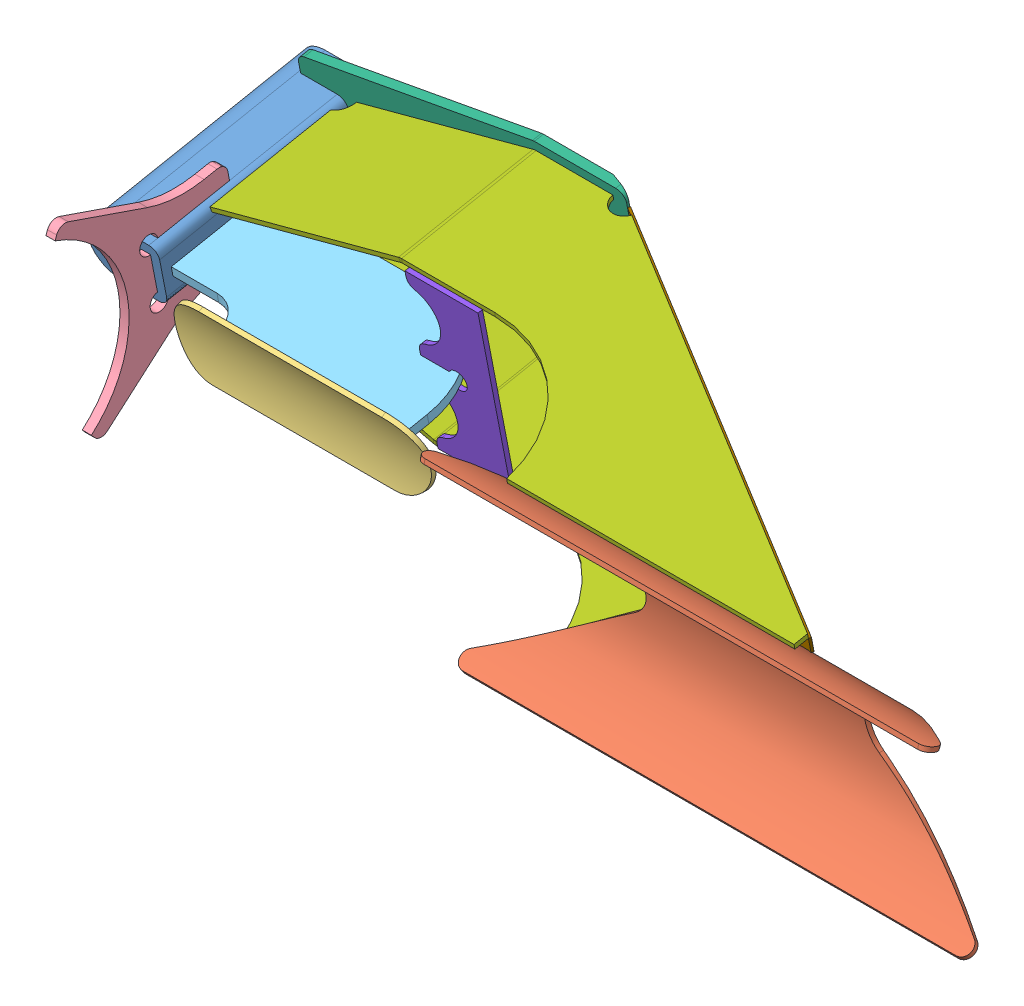
SolidWorks assembly 000012_REVD_BASE ASSY, configuration Default. Lengths in mm.
Overall size (2641.65 717.32 925.03).
12 component instances, 11 part files, 31 mates.
Components (placement in the parent):
- REVCOPTIMIZED BASE_ISO AT 0.3-1: REVCOPTIMIZED BASE_ISO AT 0.3 [Default] at origin (suppressed, hidden)
- REVCOPTIMIZED BASE_ISO AT 0.4-1: REVCOPTIMIZED BASE_ISO AT 0.4 [Default] at origin (suppressed, hidden)
- REVC000012_BEARING, BASE-1: REVC000012_BEARING, BASE [PLAIN BEARINGS] x (1 0 0) z (0 -0.190809 0.981627) size (209.55 152.4 609.6)
- REVC000012_BASE DOUBLER PLATE 1-1: REVC000012_BASE DOUBLER PLATE 1 [Default] x (1 0 0) z (0 -0.190809 0.981627) size (1422.49 583.91 197.71)
- REVC000012_BASE DOUBLER PLATE 3-1: REVC000012_BASE DOUBLER PLATE 3 [Default] at (-63.5 0 0) x (1 0 0) z (0 0.190809 -0.981627) size (711.26 207.83 29.54)
- REVC000012_BASE PLATE 13-1: REVC000012_BASE PLATE 13 [Default] at (82.55 0 0) x (1 0 0) z (0 -0.190809 0.981627) size (25.4 575.33 457.2)
- REVC000012_BASE PLATE 11-1: REVC000012_BASE PLATE 11 [Default] at (133.35 0 0) x (1 0 0) z (0 -0.190809 0.981627) size (711.2 25.4 355.6)
- REVC000012_BASE PLATE 10-1: REVC000012_BASE PLATE 10 [Default] at (6.35 174.4757 -897.5999) x (1 0 0) z (0 -0.190809 0.981627) size (939.8 558.8 25.4)
- REVC000012_BASE PLATES 6,7-1: REVC000012_BASE PLATES 6,7 [Default] at (692.15 -236.8666 -46.0422) x (1 0 0) z (0 -0.190809 0.981627) size (1978.96 191.65 708.05)
- REVC000012_BASE PLATES 6,7-2: REVC000012_BASE PLATES 6,7 [OPP HAND] at (692.15 236.8666 46.0422) x (1 0 0) z (0 -0.190809 0.981627) size (1978.96 191.65 708.05)
- REVC000012_BASE PLATE 14-1: REVC000012_BASE PLATE 14 [Default] at (714.0997 100.5659 -517.3666) x (0 0.190809 -0.981627) z (1 0 0) size (12.7 482.6 203.2)
- REVC000012_BASE PLATES 4,5-3: REVC000012_BASE PLATES 4,5 [WIDTH 2] at (2529.9373 0 0) x (1 0 0) z (0 0.190809 -0.981627) size (1163.57 482.6 675.45)
Mates (geometry in assembly coordinates):
- Coincident3: coincident aligned: plane of REVC000012_BEARING, BASE-1 through (0 0 0) normal (0 -0.190809 0.981627); plane of assembly through (0 0 0) normal (0 -0.190809 0.981627)
- Coincident4: coincident anti-aligned: plane of REVC000012_BEARING, BASE-1 through (0 0 0) normal (0 0.981627 0.190809); plane of assembly through (0 0 0) normal (0 -0.981627 -0.190809)
- Coincident5: coincident aligned: plane of REVC000012_BEARING, BASE-1; plane of assembly through (0 0 0) normal (1 0 0)
- Coincident6: coincident aligned: plane of REVC000012_BASE DOUBLER PLATE 1-1 through (321.1511 -321.1511 0) normal (0 0 1); plane of assembly through (0 0 0) normal (1 0 0)
- Coincident7: coincident anti-aligned: plane of REVC000012_BASE DOUBLER PLATE 1-1 through (0 0 0) normal (0 0.981627 0.190809); plane of assembly through (0 0 0) normal (0 -0.981627 -0.190809)
- Coincident8: coincident aligned: plane of REVC000012_BASE DOUBLER PLATE 1-1 through (0 0 0) normal (0 -0.190809 0.981627); plane of assembly through (0 0 0) normal (0 -0.190809 0.981627)
- Coincident16: coincident anti-aligned: plane of REVC000012_BASE DOUBLER PLATE 3-1 through (-63.5 0 0) normal (0 0.190809 -0.981627); plane of assembly through (0 0 0) normal (0 -0.190809 0.981627)
- Coincident18: coincident aligned: plane of REVC000012_BASE DOUBLER PLATE 3-1 through (-63.5 0 0) normal (0 -0.981627 -0.190809); plane of assembly through (0 0 0) normal (0 -0.981627 -0.190809)
- Distance3: distance = 63.5 mm aligned: plane of REVC000012_BASE DOUBLER PLATE 3-1; plane of assembly through (0 0 0) normal (1 0 0)
- Coincident20: coincident aligned: plane of REVC000012_BASE PLATE 13-1 through (82.55 0 0) normal (0 -0.190809 0.981627); plane of assembly through (0 0 0) normal (0 -0.190809 0.981627)
- Coincident21: coincident anti-aligned: plane of REVC000012_BASE PLATE 13-1 through (82.55 0 0) normal (0 0.981627 0.190809); plane of assembly through (0 0 0) normal (0 -0.981627 -0.190809)
- Distance1: distance = 82.55 mm aligned: plane of REVC000012_BASE PLATE 13-1 through (316.4294 -316.4294 82.55) normal (0 0 1); plane of assembly through (0 0 0) normal (1 0 0)
- Coincident23: coincident anti-aligned: plane of REVC000012_BASE PLATE 11-1 through (133.35 0 0) normal (0 0.981627 0.190809); plane of assembly through (0 0 0) normal (0 -0.981627 -0.190809)
- Coincident24: coincident aligned: plane of REVC000012_BASE PLATE 11-1 through (133.35 0 0) normal (0 -0.190809 0.981627); plane of assembly through (0 0 0) normal (0 -0.190809 0.981627)
- Distance2: distance = 133.35 mm aligned: plane of REVC000012_BASE PLATE 11-1 through (13.97 -13.97 133.35) normal (0 0 1); plane of assembly through (0 0 0) normal (1 0 0)
- Coincident25: coincident anti-aligned: plane of REVC000012_BASE PLATE 10-1 through (6.35 174.4757 -897.5999) normal (0 0.981627 0.190809); plane of assembly through (0 0 0) normal (0 -0.981627 -0.190809)
- Distance4: distance = 914.4 mm aligned: plane of assembly through (0 0 0) normal (0 -0.190809 0.981627); plane of REVC000012_BASE PLATE 10-1 through (6.35 174.4757 -897.5999) normal (0 -0.190809 0.981627)
- Distance5: distance = 6.35 mm aligned: plane of REVC000012_BASE PLATE 10-1; plane of assembly through (0 0 0) normal (1 0 0)
- Distance10: distance = 241.3 mm anti-aligned: plane of assembly through (0 0 0) normal (0 -0.981627 -0.190809); plane of REVC000012_BASE PLATES 6,7-1 through (692.15 -236.8666 -46.0422) normal (0 0.981627 0.190809)
- Coincident49: coincident aligned: plane of REVC000012_BASE PLATES 6,7-1 through (692.15 -236.8666 -46.0422) normal (0 -0.190809 0.981627); plane of assembly through (0 0 0) normal (0 -0.190809 0.981627)
- Distance11: distance = 692.15 mm aligned: plane of REVC000012_BASE PLATES 6,7-1; plane of assembly through (0 0 0) normal (1 0 0)
- Coincident65: coincident aligned: plane of REVC000012_BASE PLATES 6,7-2 through (692.15 236.8666 46.0422) normal (0 -0.190809 0.981627); plane of assembly through (0 0 0) normal (0 -0.190809 0.981627)
- Distance16: distance = 241.3 mm anti-aligned: plane of REVC000012_BASE PLATES 6,7-2 through (692.15 236.8666 46.0422) normal (0 0.981627 0.190809); plane of assembly through (0 0 0) normal (0 -0.981627 -0.190809)
- Distance18: distance = 692.15 mm aligned: plane of REVC000012_BASE PLATES 6,7-2; plane of assembly through (0 0 0) normal (1 0 0)
- Coincident69: coincident anti-aligned: plane of REVC000012_BASE PLATE 14-1; plane of assembly through (0 0 0) normal (0 -0.981627 -0.190809)
- Coincident70: coincident: circle of REVC000012_BASE PLATE 11-1; point of REVC000012_BASE PLATE 14-1
- Coincident72: coincident: circle of REVC000012_BASE PLATE 11-1; point of REVC000012_BASE PLATE 14-1
- Distance19: distance = 527.05 mm anti-aligned: plane of REVC000012_BASE PLATE 14-1; plane of assembly through (0 0 0) normal (0 -0.190809 0.981627)
- Coincident73: coincident anti-aligned: plane of REVC000012_BASE PLATES 4,5-3 through (2529.9373 0 0) normal (0 0.190809 -0.981627); plane of assembly through (0 0 0) normal (0 -0.190809 0.981627)
- Coincident74: coincident aligned: plane of REVC000012_BASE PLATES 4,5-3 through (2529.9373 0 0) normal (0 -0.981627 -0.190809); plane of assembly through (0 0 0) normal (0 -0.981627 -0.190809)
- Distance20: distance = 2529.9373 mm aligned: plane of REVC000012_BASE PLATES 4,5-3; plane of assembly through (0 0 0) normal (1 0 0)
